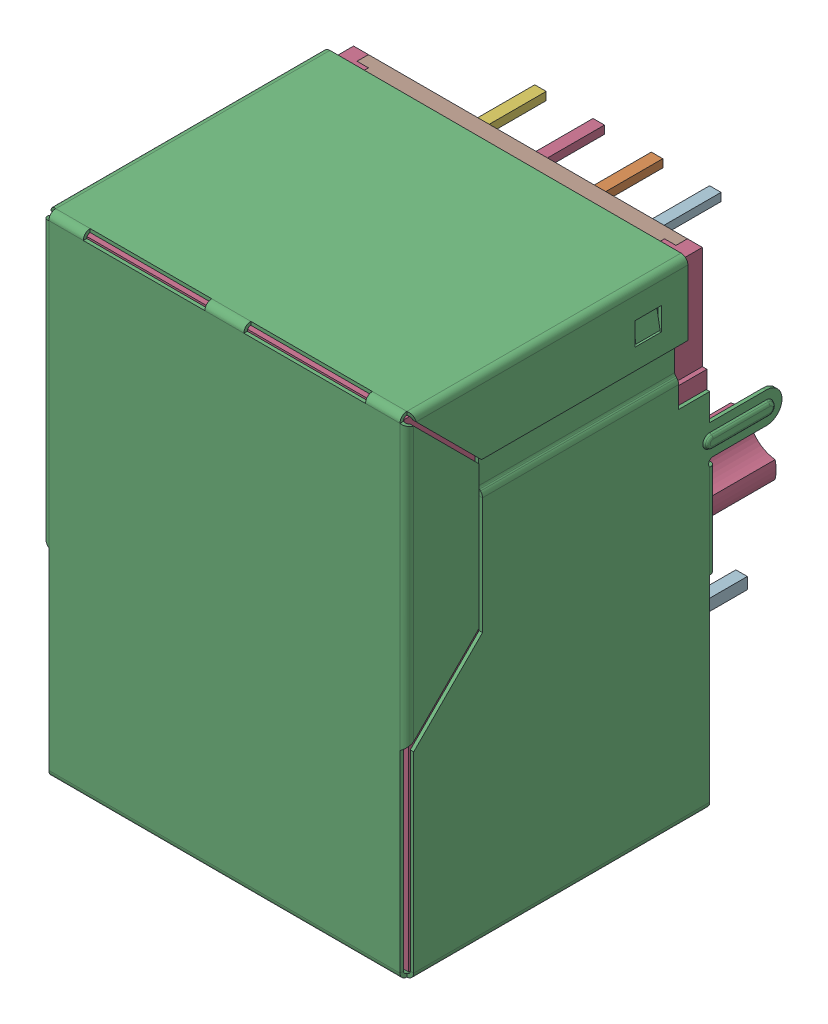
SolidWorks assembly EDAC_1743_RJ45_TH.stp, configuration Default. Lengths in mm.
Overall size (16.2 21.37 16.96).
11 component instances, 8 part files, 0 mates.
Components (placement in the parent):
- wiring.stp-1: wiring.stp [Default] at origin size (13.9 18.75 15.99)
  - rj45.stp-1: rj45.stp [Default] at origin size (13.46 13.45 4.49)
  - magnetics.stp-1: magnetics.stp [Default] at origin size (11.5 6.5 11.5)
  - leads_3.stp-1: leads_3.stp [Default] at origin size (13.9 7.95 8.72)
- lights.stp-1: lights.stp [Default] at origin size (13.8 6.61 5.6)
  - led_org.stp-1: led_org.stp [Default] at (-5.37 0 2.2) size (3.04 5.2 4.86)
  - led_org.stp-2: led_org.stp [Default] at (5.37 0 2.2) size (3.04 5.2 4.86)
  - lights-0.stp-1: lights-0.stp [Default] at origin size (3.06 4.17 2.2)
  - lights-1.stp-1: lights-1.stp [Default] at origin size (3.06 4.17 2.2)
- shell_3.stp-1: shell_3.stp [Default] at origin size (16.2 21.37 16.36)
- base_1.stp-1: base_1.stp [Default] at origin size (15.6 20.75 16.5)
